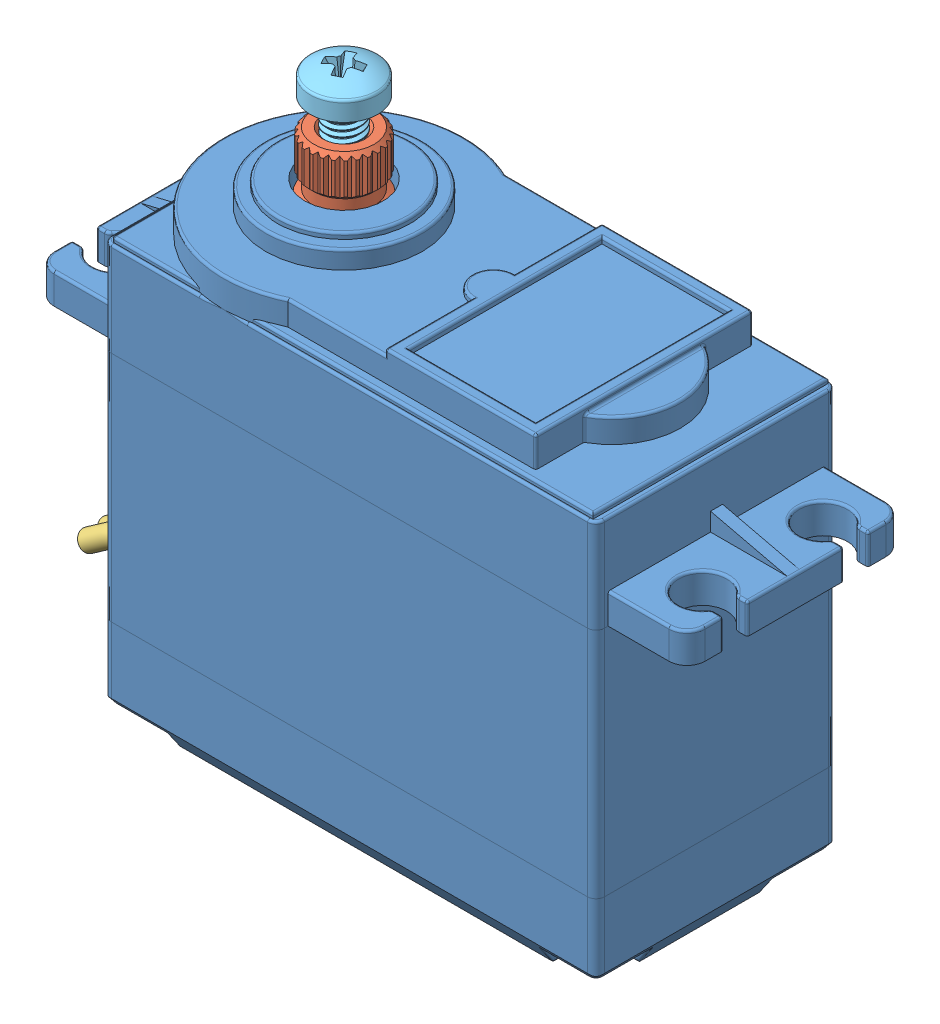
SolidWorks assembly MG996R Servo Motor, configuration Default. Lengths in mm.
Overall size (57.44 47.35 20).
8 component instances, 5 part files, 18 mates.
Components (placement in the parent):
- Case-1: Case [Default] at origin size (54 39 20)
- Output Shaft-1: Output Shaft [Default] at (-10.45 9.35 0) x (0.84541 0 0.534117) z (-0.534117 0 0.84541) size (13.78 15.2 13.78)
- Rubber Wire Cable Sleeve-1: Rubber Wire Cable Sleeve [Default] at (-18.2 -12.025 0) size (15.24 5.03 7.75)
- Pan Head Cross Screw M1.6-1: Pan Head Cross Screw M1.6 [Default] at (-17.575 12.35 7.125) x (0 1 0) z (0.509945 0 0.860207) size (32.17 3.2 3.2)
- Pan Head Cross Screw M1.6-2: Pan Head Cross Screw M1.6 [Default] at (17.575 12.35 7.125) x (0 1 0) z (0.498431 0 0.86693) size (32.17 3.2 3.2)
- Pan Head Cross Screw M1.6-3: Pan Head Cross Screw M1.6 [Default] at (17.575 12.35 -7.125) x (0 1 0) z (0.499198 0 0.866488) size (32.17 3.2 3.2)
- Pan Head Cross Screw M1.6-4: Pan Head Cross Screw M1.6 [Default] at (-17.575 12.35 -7.125) x (0 1 0) z (0.500246 0 0.865884) size (32.17 3.2 3.2)
- Pan Head Cross Screw M3-1: Pan Head Cross Screw M3 [Default] at (-10.45 20.85 0) x (0 -1 0) z (0.893136 0 -0.449786) size (8.51 5.6 5.6)
Mates (geometry in assembly coordinates):
- Concentric1: concentric aligned: cylinder of Case-1 through (-10.45 -18.151 0) axis (0 1 0) radius 3.25; cylinder of Output Shaft-1 through (-10.45 14.8629 0) axis (0 1 0) radius 3
- Distance1: distance = 3.7 mm aligned: plane of Output Shaft-1 through (-8.9705 24.55 0.9347) normal (0 1 0); plane of Case-1 through (-10.45 20.85 0) normal (0 1 0)
- Coincident1: coincident anti-aligned: plane of Case-1 through (0 -13.4 0) normal (0 1 0); plane of Rubber Wire Cable Sleeve-1 through (-20.45 -13.4 2.9) normal (0 -1 0)
- Coincident2: coincident: plane of Case-1 through (-20.45 -13.4 -2.9) normal (0 0 1); plane of Rubber Wire Cable Sleeve-1 through (-20.45 -13.4 -2.9) normal (0 0 -1)
- Coincident4: coincident: plane of Case-1 through (-20.45 -18.15 10) normal (-1 0 0); plane of Rubber Wire Cable Sleeve-1 through (-20.45 -12.025 0) normal (1 0 0)
- Concentric2: concentric aligned: cylinder of Case-1 through (-17.575 19.632 7.125) axis (0 -1 0) radius 1.125; cylinder of Pan Head Cross Screw-1 through (-17.575 9.998 7.125) axis (0 -1 0) radius 1.6
- Screw1: screw = 0.35 mm aligned: cylinder of Case-1 through (-17.575 16.632 7.125) axis (0 -1 0) radius 0.8; cylinder of Pan Head Cross Screw-1 through (-17.575 9.998 7.125) axis (0 -1 0) radius 0.8
- Coincident5: coincident anti-aligned: plane of Case-1 through (-17.575 -16.65 7.125) normal (0 -1 0); plane of Pan Head Cross Screw-1 through (-17.167 -16.65 7.8132) normal (0 1 0)
- Concentric3: concentric aligned: cylinder of Case-1 through (17.575 19.632 7.125) axis (0 -1 0) radius 1.125; cylinder of Pan Head Cross Screw-2 through (17.575 9.998 7.125) axis (0 -1 0) radius 1.6
- Screw2: screw = 0.35 mm aligned: cylinder of Case-1 through (17.575 16.632 7.125) axis (0 -1 0) radius 0.8; cylinder of Pan Head Cross Screw-2 through (17.575 9.998 7.125) axis (0 -1 0) radius 0.8
- Coincident6: coincident anti-aligned: plane of Case-1 through (17.575 -16.65 7.125) normal (0 -1 0); plane of Pan Head Cross Screw-2 through (17.9737 -16.65 7.8185) normal (0 1 0)
- Concentric4: concentric aligned: cylinder of Case-1 through (17.575 19.632 -7.125) axis (0 -1 0) radius 1.125; cylinder of Pan Head Cross Screw-3 through (17.575 9.998 -7.125) axis (0 -1 0) radius 1.6
- Screw3: screw = 0.35 mm aligned: cylinder of Case-1 through (17.575 16.632 -7.125) axis (0 -1 0) radius 0.8; cylinder of Pan Head Cross Screw-3 through (17.575 9.998 -7.125) axis (0 -1 0) radius 0.8
- Coincident7: coincident anti-aligned: plane of Case-1 through (17.575 -16.65 -7.125) normal (0 -1 0); plane of Pan Head Cross Screw-3 through (17.9744 -16.65 -6.4318) normal (0 1 0)
- Concentric5: concentric aligned: cylinder of Case-1 through (-17.575 19.632 -7.125) axis (0 -1 0) radius 1.125; cylinder of Pan Head Cross Screw-4 through (-17.575 9.998 -7.125) axis (0 -1 0) radius 1.6
- Screw4: screw = 0.35 mm aligned: cylinder of Case-1 through (-17.575 16.632 -7.125) axis (0 -1 0) radius 0.8; cylinder of Pan Head Cross Screw-4 through (-17.575 9.998 -7.125) axis (0 -1 0) radius 0.8
- Coincident8: coincident anti-aligned: plane of Case-1 through (-17.575 -16.65 -7.125) normal (0 -1 0); plane of Pan Head Cross Screw-4 through (-17.1748 -16.65 -6.4323) normal (0 1 0)
- Screw5: screw = 0.5 mm aligned: cylinder of Output Shaft-1 through (-10.45 14.8629 0) axis (0 1 0) radius 1.5; cylinder of Pan Head Cross Screw M3-1 through (-10.45 23.202 0) axis (0 1 0) radius 1.5
